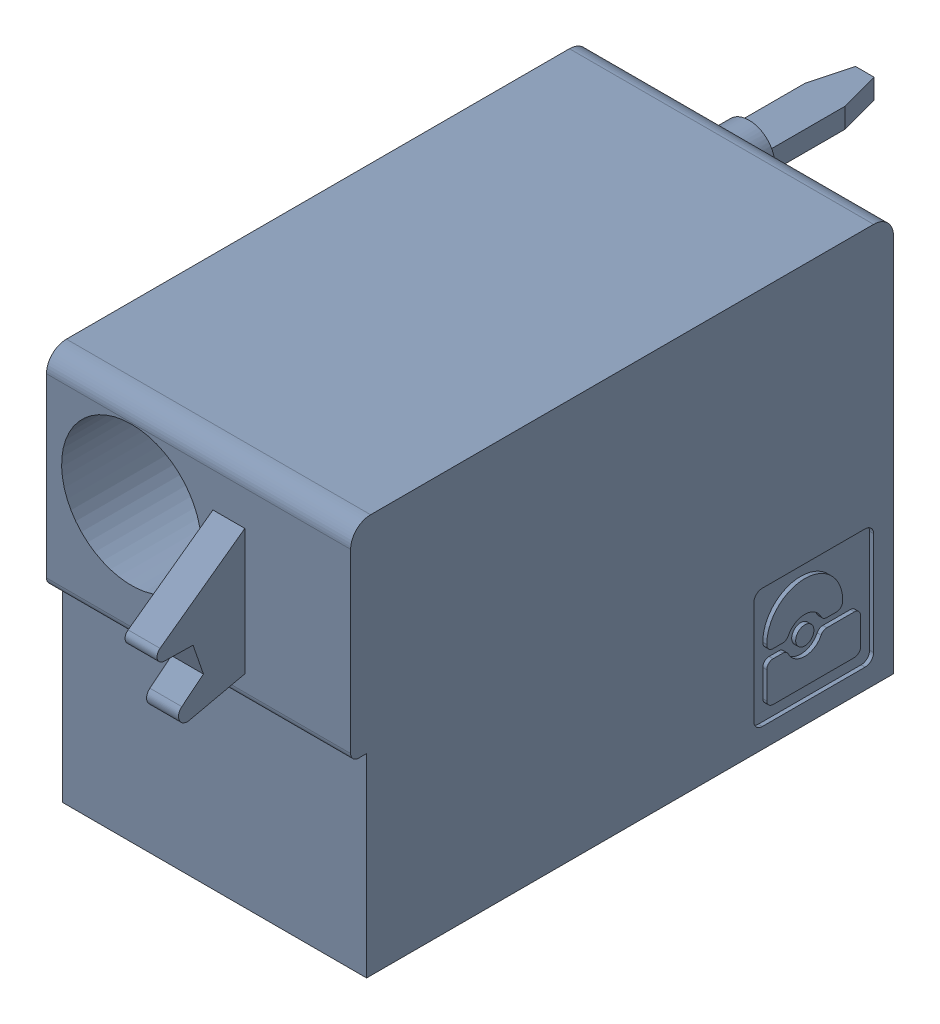
SolidWorks assembly J85, configuration Default. Lengths in mm.
Overall size (7.62 10 19.2).
2 component instances, 1 part files, 0 mates.
Components (placement in the parent):
- 1790487-1: 1790487 [Default] at (231.545 -5.67 -10.6) x (0 1 0) z (1 0 0) size (10 19.2 7.62)
  - ffkdsa1-v2-7.62-1: ffkdsa1-v2-7.62 [Default] at (-15.6914 -27.508 9.12) x (0 -1 0) z (0 0 1) size (19.2 10 7.62)
